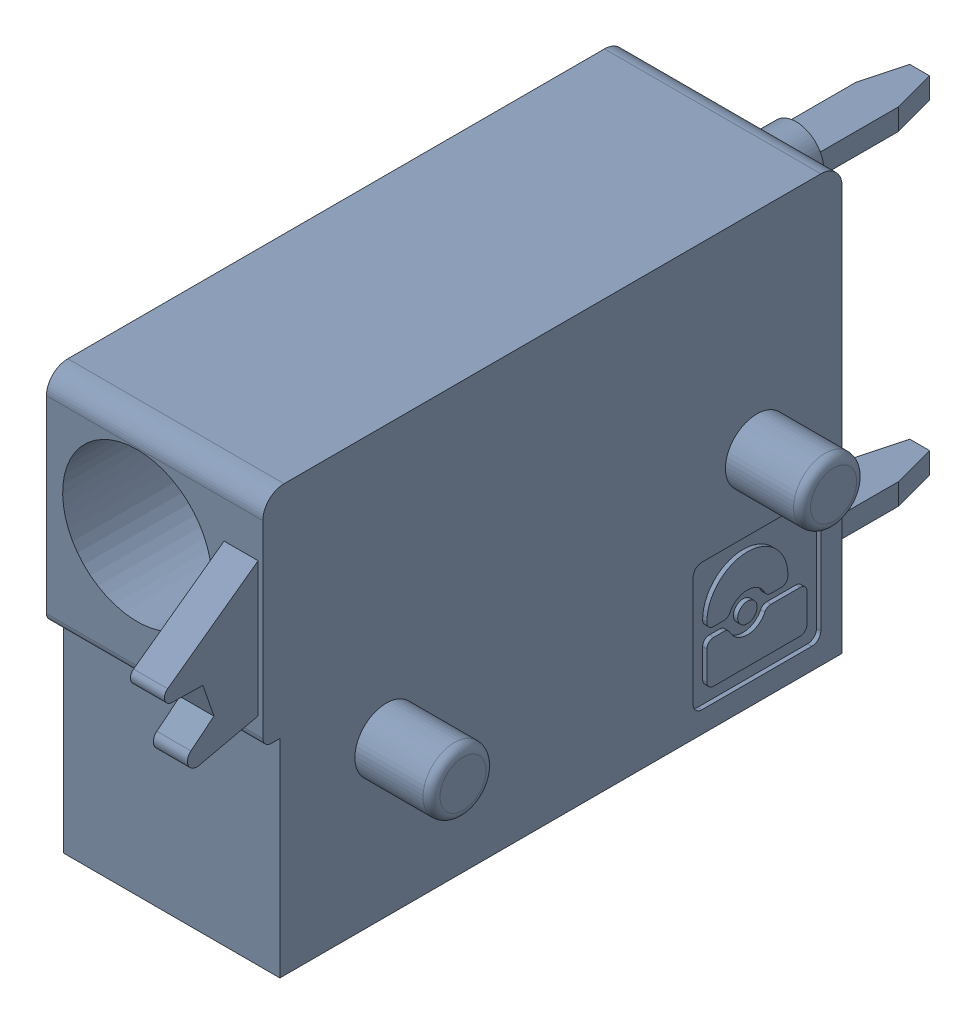
SolidWorks assembly J47, configuration Default. Lengths in mm.
Overall size (6.88 10 19.2).
2 component instances, 1 part files, 0 mates.
Components (placement in the parent):
- 1790348-1: 1790348 [Default] at (136.5251 -7.6199 0) x (0 1 0) z (1 0 0) size (10 19.2 6.88)
  - ffkds-v2-5.08-1: ffkds-v2-5.08 [Default] at (-23.7414 -38.158 -2.54) x (0 -1 0) z (0 0 1) size (19.2 10 6.88)
